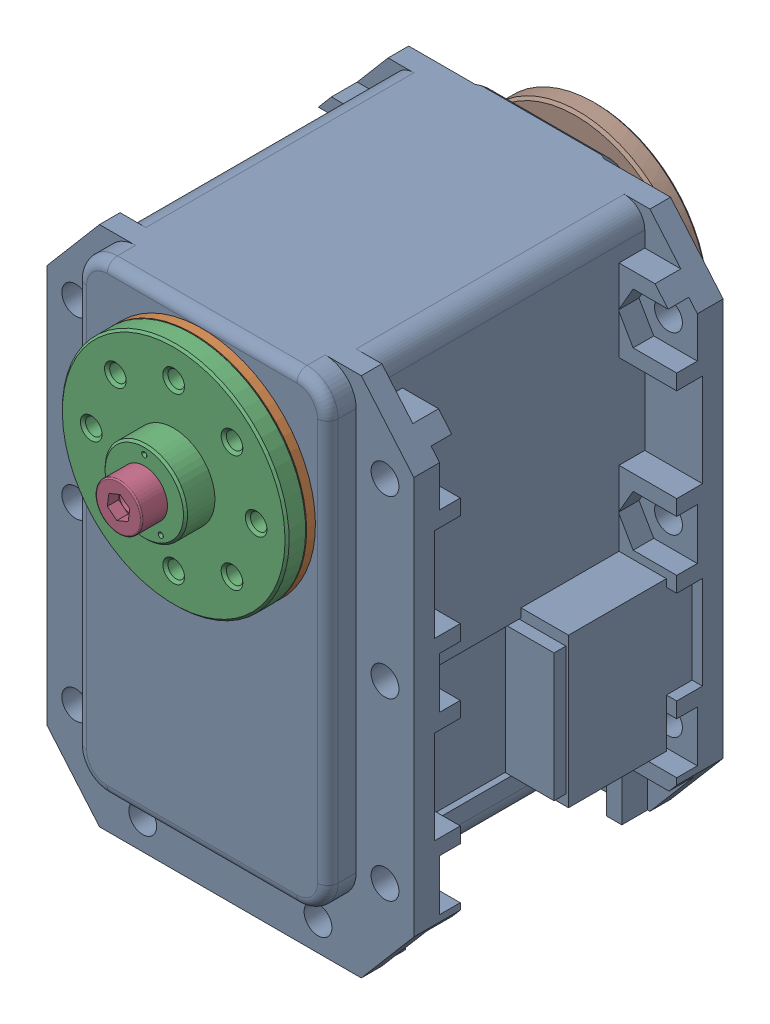
SolidWorks assembly MX-28(U)-8, configuration Default. Lengths in mm.
Overall size (35.6 54.13 48.5).
8 component instances, 7 part files, 0 mates.
Components (placement in the parent):
- dynamixel_x28series(U)-1: dynamixel_x28series(U) [Default] at origin size (35.6 50.71 41.85)
- trust_washer(U)-1: trust_washer(U) [Default] at (0 0 18.6) x (-0.666375 -0.745617 0) z (0.745617 -0.666375 0) size (22 0.85 22)
- HN07-N101(U)-1: HN07-N101(U) [Default] at (0 0 18.5) x (1 0 0) z (0 -1 0) size (22 5.85 22)
- WB_M2.5x8-1: WB_M2.5x8 [Default] at (0 0 25.85) x (0 0 -1) z (-0.991137 0.132843 0) size (10.5 4.5 4.5)
- WB_M2.5x8-2: WB_M2.5x8 [Default] at (0 0 -22.65) x (0 0 1) z (-0.936501 0.350665 0) size (10.5 4.5 4.5)
- RX28-CAP-1: RX28-CAP [Default] at (0 0 -20.35) x (-0.995735 -0.092256 0) z (0 0 -1) size (7.2 7.2 1.8)
- MF106ZZ-1: MF106ZZ [Default] at (0 0 -20.35) x (0.888333 -0.4592 0) z (-0.4592 -0.888333 0) size (11.2 3 11.2)
- HN07-i101-1: HN07-i101 [Default] at (0 0 -20.5) x (1 0 0) z (0 1 0) size (22 3.05 22)
